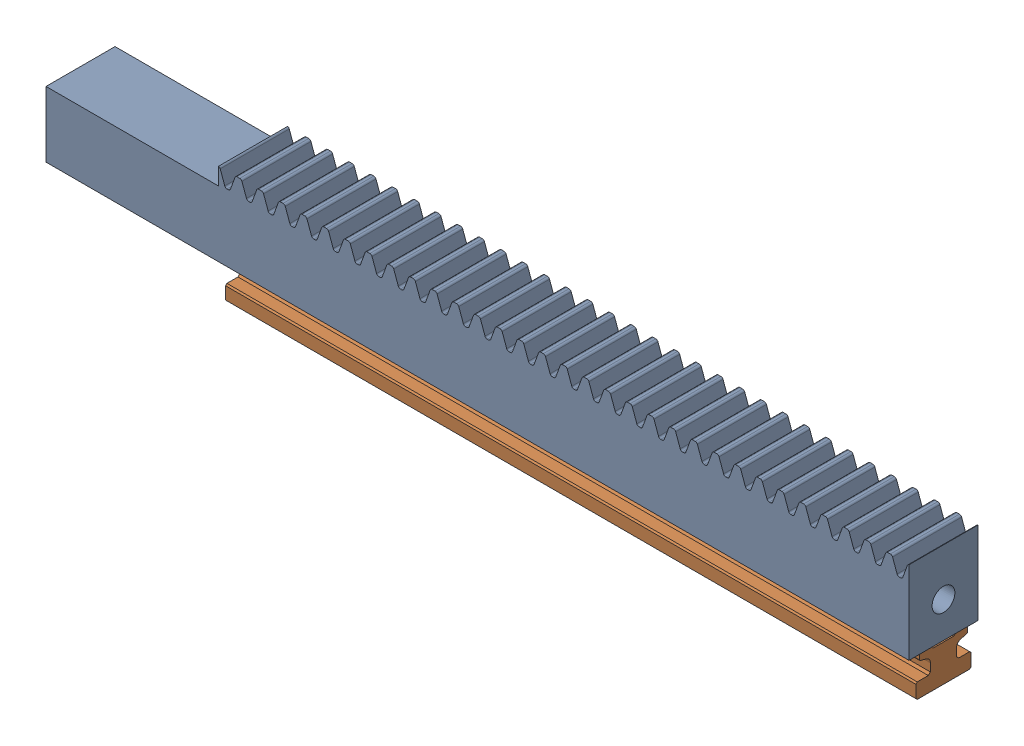
SolidWorks assembly R&PSim, configuration Default. Lengths in mm.
Overall size (125 17.5 10).
2 component instances, 2 part files, 3 mates.
Components (placement in the parent):
- 3-6-009 (2485N218_Metal Gear Rack)-1: 3-6-009 (2485N218_Metal Gear Rack) [2485N217] at (6.5599 25.9832 27.5386) size (125 12 10)
- TS_04_07_100_1-1: TS_04_07_100_1 [Default] at (6.5599 19.9832 27.5386) x (0 0 1) z (0 -1 0) size (8 100 5.5)
Mates (geometry in assembly coordinates):
- Coincident1: coincident: plane of 2485N217_Metal Gear Rack - 20 Degree Pressure Angle-1 through (-43.4401 19.9832 22.5386) normal (0 -1 0); plane of TS_04_07_100_1-1 through (56.5599 19.9832 25.0386) normal (0 1 0)
- Coincident2: coincident: plane of 2485N217_Metal Gear Rack - 20 Degree Pressure Angle-1 through (56.5599 31.9832 22.5386) normal (1 0 0); plane of TS_04_07_100_1-1 through (56.5599 17.1929 27.5386) normal (1 0 0)
- Width1: width anti-aligned: plane of TS_04_07_100_1-1 through (56.5599 15.5832 31.5386) normal (0 0 1); plane of 2485N217_Metal Gear Rack - 20 Degree Pressure Angle-1 through (56.5599 15.5832 23.5386) normal (0 0 -1); plane of TS_04_07_100_1-1 through (6.5599 25.9832 22.5386) normal (0 0 -1); plane of 2485N217_Metal Gear Rack - 20 Degree Pressure Angle-1 through (6.5599 25.9832 32.5386) normal (0 0 1)
